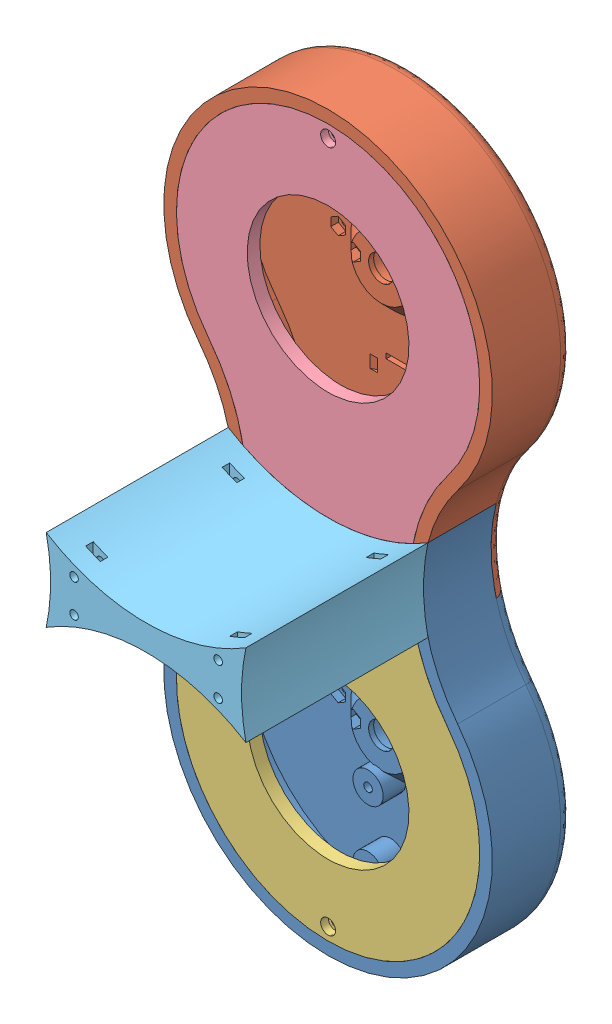
SolidWorks assembly ART2_2, configuration Predeterminado. Lengths in mm.
Overall size (130 290 113.1).
9 component instances, 7 part files, 64 mates.
Components (placement in the parent):
- Art2BodyB_Splitted_A-1: Art2BodyB_Splitted_A [Predeterminado] at (7.2829 72.9902 127.3956) x (1 0 0) z (0 -1 0) size (130 32.44 161.27)
- Art2BodyB_Splitted_B-1: Art2BodyB_Splitted_B [Predeterminado] at (7.2829 72.9902 127.3956) x (1 0 0) z (0 -1 0) size (130 32.44 161.71)
- Art2BodyBCover_Splitted_A-1: Art2BodyBCover_Splitted_A [Predeterminado] at (7.2829 72.9902 159.3956) x (-1 0 0) z (0 -1 0) size (120 7 152.99)
- Art2BodyBCover_Splitted_B-1: Art2BodyBCover_Splitted_B [Predeterminado] at (7.2829 72.9902 159.3956) x (-1 0 0) z (0 -1 0) size (120 8 152.99)
- Art2BodyUnion-1: Art2BodyUnion [Predeterminado] at (7.2829 152.9902 195.3956) x (-1 0 0) z (0 1 0) size (79 72 32.49)
- AMT-B0-W-1: AMT-B0-W [Default] at (7.2829 232.9902 123.6256) x (-0.999995 0.003209 0) z (0 0 -1) size (52.34 43.39 9.15)
- AMT-B0-W-2: AMT-B0-W [Default] at (7.2829 72.9902 123.6256) x (0.999999 -0.001499 0) z (0 0 -1) size (52.34 43.39 9.15)
- AMT-1: AMT [Default] at (7.2829 232.9902 123.6256) x (-0.999995 0.003209 0) z (0 0 -1) size (28.93 43.4 9.14)
- AMT-2: AMT [Default] at (7.2829 72.9902 123.6256) x (0.999999 -0.001499 0) z (0 0 -1) size (28.93 43.4 9.14)
Mates (geometry in assembly coordinates):
- Concéntrica1: concentric aligned: cylinder of Art2BodyB_Splitted_A-1 through (-21.2171 159.4902 109.3956) axis (0 0 1) radius 1.7; cylinder of Art2BodyB_Splitted_B-1 through (-21.2171 159.4902 109.3956) axis (0 0 1) radius 1.7
- Concéntrica2: concentric aligned: cylinder of Art2BodyB_Splitted_A-1 through (35.7829 146.4902 109.3956) axis (0 0 1) radius 1.7; cylinder of Art2BodyB_Splitted_B-1 through (35.7829 146.4902 109.3956) axis (0 0 1) radius 1.7
- Coincidente1: coincident anti-aligned: plane of Art2BodyB_Splitted_A-1 through (7.2829 72.9902 132.3956) normal (0 0 -1); plane of Art2BodyB_Splitted_B-1 through (-43.9519 192.9902 132.3956) normal (0 0 1)
- Concéntrica3: concentric anti-aligned: cylinder of Art2BodyB_Splitted_B-1 through (-3.7171 232.9902 147.3956) axis (0 0 -1) radius 1.7; cylinder of hexagon nut_3_jis-1 through (-3.7171 232.9902 134.3956) axis (0 0 1) radius 1.25
- Coincidente7: coincident anti-aligned: plane of Art2BodyB_Splitted_B-1 through (7.2829 232.9902 134.3956) normal (0 0 1); plane of hexagon nut_3_jis-1 through (-9.2171 232.9902 134.3956) normal (0 0 -1)
- Concéntrica16: concentric anti-aligned: cylinder of Art2BodyB_Splitted_A-1 through (7.2829 72.9902 136.3956) axis (0 0 -1) radius 8.2; cylinder of radial ball bearing_68_skf-1 through (7.2829 72.9902 113.2581) axis (0 0 1) radius 2.5
- Coincidente19: coincident anti-aligned: plane of Art2BodyB_Splitted_A-1 through (7.2829 72.9902 136.3956) normal (0 0 -1); plane of radial ball bearing_68_skf-1 through (7.2829 75.7902 136.3956) normal (0 0 1)
- Concéntrica17: concentric aligned: cylinder of Art2BodyB_Splitted_B-1 through (18.2829 232.9902 147.3956) axis (0 0 -1) radius 1.7; cylinder of CommonBearingFixThrough-1 through (18.2829 232.9902 130.3956) axis (0 0 -1) radius 2.95
- Concéntrica18: concentric aligned: cylinder of Art2BodyB_Splitted_B-1 through (-3.7171 232.9902 147.3956) axis (0 0 -1) radius 1.7; cylinder of CommonBearingFixThrough-1 through (-3.7171 232.9902 130.3956) axis (0 0 -1) radius 2.95
- Coincidente21: coincident aligned: plane of Art2BodyB_Splitted_B-1 through (7.2829 232.9902 131.3956) normal (0 0 -1); circle of CommonBearingFixThrough-1
- Concéntrica19: concentric aligned: cylinder of Art2BodyB_Splitted_A-1 through (18.2829 72.9902 147.3956) axis (0 0 -1) radius 1.7; cylinder of CommonBearingFixThrough-2 through (18.2829 72.9902 130.3956) axis (0 0 -1) radius 2.95
- Concéntrica20: concentric aligned: cylinder of Art2BodyB_Splitted_A-1 through (-3.7171 72.9902 147.3956) axis (0 0 -1) radius 1.7; cylinder of CommonBearingFixThrough-2 through (-3.7171 72.9902 130.3956) axis (0 0 -1) radius 2.95
- Coincidente22: coincident aligned: plane of Art2BodyB_Splitted_A-1 through (7.2829 72.9902 131.3956) normal (0 0 -1); circle of CommonBearingFixThrough-2
- Coincidente29: coincident aligned: plane of socket head cap screw_am-7 through (4.0295 58.1304 143.0356) normal (0 0 -1); plane of socket head cap screw_am-8 through (4.0295 30.1304 143.0356) normal (0 0 -1)
- Coincidente32: coincident aligned: plane of socket head cap screw_am-5 through (8.4295 252.9304 143.0356) normal (0 0 -1); plane of socket head cap screw_am-6 through (9.4829 281.1402 143.0356) normal (0 0 -1)
- Concéntrica32: concentric aligned: cylinder of Art2BodyBCover_Splitted_A-1 through (-21.2171 146.4902 154.3956) axis (0 0 1) radius 1.7; cylinder of Art2BodyBCover_Splitted_B-1 through (-21.2171 146.4902 151.3956) axis (0 0 1) radius 1.7
- Concéntrica33: concentric aligned: cylinder of Art2BodyBCover_Splitted_A-1 through (35.7829 159.4902 154.3956) axis (0 0 1) radius 1.7; cylinder of Art2BodyBCover_Splitted_B-1 through (35.7829 159.4902 151.3956) axis (0 0 1) radius 1.7
- Coincidente34: coincident anti-aligned: plane of Art2BodyBCover_Splitted_A-1 through (-43.9519 112.9902 154.3956) normal (0 0 -1); plane of Art2BodyBCover_Splitted_B-1 through (58.5177 112.9902 154.3956) normal (0 0 1)
- Concéntrica34: concentric aligned: circle of Art2BodyB_Splitted_A-1; cylinder of Art2BodyBCover_Splitted_A-1 through (7.2829 17.9902 156.3956) axis (0 0 1) radius 2.95
- Concéntrica35: concentric aligned: cylinder of Art2BodyB_Splitted_B-1 through (7.2829 287.9902 136.3956) axis (0 0 1) radius 1.7; cylinder of Art2BodyBCover_Splitted_B-1 through (7.2829 287.9902 156.3956) axis (0 0 1) radius 2.95
- Coincidente35: coincident anti-aligned: plane of Art2BodyB_Splitted_B-1 through (7.2829 232.9902 152.3956) normal (0 0 1); plane of Art2BodyBCover_Splitted_B-1 through (7.2829 232.9902 152.3956) normal (0 0 -1)
- Concéntrica36: concentric anti-aligned: cylinder of Art2BodyBCover_Splitted_B-1 through (7.2829 287.9902 171.3956) axis (0 0 -1) radius 1.7; cylinder of socket head cap screw_am-9 through (7.2829 287.9902 191.1456) axis (0 0 1) radius 1.5
- Coincidente36: coincident anti-aligned: plane of Art2BodyBCover_Splitted_B-1 through (7.2829 287.9902 156.3956) normal (0 0 1); plane of socket head cap screw_am-9 through (7.2829 290.7402 156.3956) normal (0 0 -1)
- Concéntrica37: concentric aligned: cylinder of Art2BodyBCover_Splitted_A-1 through (7.2829 17.9902 156.3956) axis (0 0 1) radius 2.95; cylinder of socket head cap screw_am-10 through (7.2829 17.9902 191.1456) axis (0 0 1) radius 1.5
- Coincidente37: coincident anti-aligned: plane of Art2BodyBCover_Splitted_A-1 through (7.2829 17.9902 156.3956) normal (0 0 1); plane of socket head cap screw_am-10 through (6.2295 20.5304 156.3956) normal (0 0 -1)
- Concéntrica38: concentric anti-aligned: cylinder of Art2BodyUnion-1 through (-21.2171 159.4902 189.3956) axis (0 0 -1) radius 1.7; cylinder of hexagon nut_3_jis-11 through (-21.2171 159.4902 166.8956) axis (0 0 1) radius 1.25
- Concéntrica39: concentric anti-aligned: cylinder of Art2BodyUnion-1 through (-21.2171 146.4902 189.3956) axis (0 0 -1) radius 1.7; cylinder of hexagon nut_3_jis-12 through (-21.2171 146.4902 166.8956) axis (0 0 1) radius 1.25
- Concéntrica40: concentric anti-aligned: cylinder of Art2BodyUnion-1 through (35.7829 146.4902 189.3956) axis (0 0 -1) radius 1.7; cylinder of hexagon nut_3_jis-13 through (35.7829 146.4902 166.8956) axis (0 0 1) radius 1.25
- Concéntrica41: concentric anti-aligned: cylinder of Art2BodyUnion-1 through (35.7829 159.4902 189.3956) axis (0 0 -1) radius 1.7; cylinder of hexagon nut_3_jis-18 through (35.7829 159.4902 166.8956) axis (0 0 1) radius 1.25
- Concéntrica42: concentric aligned: cylinder of Art2BodyUnion-1 through (-21.2171 159.4902 201.3956) axis (0 0 1) radius 1.7; cylinder of hexagon nut_3_jis-14 through (-21.2171 159.4902 222.0956) axis (0 0 1) radius 1.25
- Concéntrica43: concentric aligned: cylinder of Art2BodyUnion-1 through (-21.2171 146.4902 201.3956) axis (0 0 1) radius 1.7; cylinder of hexagon nut_3_jis-15 through (-21.2171 146.4902 222.0956) axis (0 0 1) radius 1.25
- Concéntrica44: concentric aligned: cylinder of Art2BodyUnion-1 through (35.7829 146.4902 201.3956) axis (0 0 1) radius 1.7; cylinder of hexagon nut_3_jis-16 through (35.7829 146.4902 222.0956) axis (0 0 1) radius 1.25
- Concéntrica45: concentric aligned: cylinder of Art2BodyUnion-1 through (35.7829 159.4902 201.3956) axis (0 0 1) radius 1.7; cylinder of hexagon nut_3_jis-17 through (35.7829 159.4902 222.0956) axis (0 0 1) radius 1.25
- Coincidente38: coincident aligned: plane of hexagon nut_3_jis-13 through (30.2829 146.4902 166.8956) normal (0 0 -1); plane of hexagon nut_3_jis-18 through (30.2829 159.4902 166.8956) normal (0 0 -1)
- Coincidente39: coincident aligned: plane of hexagon nut_3_jis-12 through (-26.7171 146.4902 166.8956) normal (0 0 -1); plane of hexagon nut_3_jis-13 through (30.2829 146.4902 166.8956) normal (0 0 -1)
- Coincidente40: coincident anti-aligned: circle of hexagon nut_3_jis-11; plane of hexagon nut_3_jis-18 through (30.2829 159.4902 166.8956) normal (0 0 -1)
- Coincidente41: coincident anti-aligned: plane of Art2BodyUnion-1 through (7.2829 152.9902 166.8956) normal (0 0 1); plane of hexagon nut_3_jis-11 through (-26.7171 159.4902 166.8956) normal (0 0 -1)
- Coincidente42: coincident aligned: plane of hexagon nut_3_jis-14 through (-26.7171 159.4902 223.8956) normal (0 0 1); circle of hexagon nut_3_jis-15
- Coincidente43: coincident aligned: plane of hexagon nut_3_jis-14 through (-26.7171 159.4902 223.8956) normal (0 0 1); plane of hexagon nut_3_jis-17 through (30.2829 159.4902 223.8956) normal (0 0 1)
- Coincidente44: coincident aligned: plane of hexagon nut_3_jis-16 through (30.2829 146.4902 223.8956) normal (0 0 1); plane of hexagon nut_3_jis-17 through (30.2829 159.4902 223.8956) normal (0 0 1)
- Coincidente45: coincident anti-aligned: plane of Art2BodyUnion-1 through (7.2829 152.9902 223.8956) normal (0 0 -1); plane of hexagon nut_3_jis-16 through (30.2829 146.4902 223.8956) normal (0 0 1)
- Concéntrica46: concentric anti-aligned: cylinder of Art2BodyBCover_Splitted_A-1 through (-21.2171 159.4902 154.3956) axis (0 0 1) radius 1.7; cylinder of Art2BodyUnion-1 through (-21.2171 159.4902 189.3956) axis (0 0 -1) radius 1.7
- Concéntrica47: concentric anti-aligned: cylinder of Art2BodyBCover_Splitted_A-1 through (35.7829 146.4902 154.3956) axis (0 0 1) radius 1.7; cylinder of Art2BodyUnion-1 through (35.7829 146.4902 189.3956) axis (0 0 -1) radius 1.7
- Coincidente46: coincident anti-aligned: plane of Art2BodyBCover_Splitted_A-1 through (-43.9519 112.9902 159.3956) normal (0 0 1); plane of Art2BodyUnion-1 through (64.7829 192.9902 159.3956) normal (0 0 -1)
- Concéntrica48: concentric anti-aligned: cylinder of Art2BodyB_Splitted_B-1 through (-21.2171 159.4902 109.3956) axis (0 0 1) radius 1.7; cylinder of socket head cap screw_am-13 through (-21.2171 159.4902 95.5456) axis (0 0 -1) radius 1.5
- Concéntrica49: concentric anti-aligned: cylinder of Art2BodyB_Splitted_B-1 through (35.7829 159.4902 109.3956) axis (0 0 1) radius 1.7; cylinder of socket head cap screw_am-11 through (35.7829 159.4902 95.5456) axis (0 0 -1) radius 1.5
- Concéntrica50: concentric anti-aligned: cylinder of Art2BodyB_Splitted_B-1 through (-21.2171 146.4902 109.3956) axis (0 0 1) radius 1.7; cylinder of socket head cap screw_am-14 through (-21.2171 146.4902 95.5456) axis (0 0 -1) radius 1.5
- Concéntrica51: concentric anti-aligned: cylinder of Art2BodyB_Splitted_B-1 through (35.7829 146.4902 109.3956) axis (0 0 1) radius 1.7; cylinder of socket head cap screw_am-12 through (35.7829 146.4902 95.5456) axis (0 0 -1) radius 1.5
- Coincidente47: coincident aligned: circle of socket head cap screw_am-11; plane of socket head cap screw_am-13 through (-21.2171 159.4902 127.2956) normal (0 0 -1)
- Coincidente48: coincident aligned: plane of socket head cap screw_am-13 through (-21.2171 159.4902 127.2956) normal (0 0 -1); plane of socket head cap screw_am-14 through (-21.2171 146.4902 127.2956) normal (0 0 -1)
- Coincidente49: coincident: point of socket head cap screw_am-12; plane of socket head cap screw_am-14 through (-21.2171 146.4902 127.2956) normal (0 0 -1)
- Coincidente50: coincident anti-aligned: plane of Art2BodyB_Splitted_B-1 through (35.7829 159.4902 130.2956) normal (0 0 -1); plane of socket head cap screw_am-11 through (38.0657 157.9567 130.2956) normal (0 0 1)
- Concéntrica52: concentric anti-aligned: circle of CommonBearingFixThrough-2; circle of AMT-B0-W-2
- Coincidente51: coincident anti-aligned: plane of Art2BodyB_Splitted_A-1 through (58.5177 112.9902 127.3956) normal (0 0 -1); plane of AMT-B0-W-2 through (7.2985 83.4102 127.3956) normal (0 0 1)
- Concéntrica53: concentric aligned: cylinder of CommonBearingFixThrough-1 through (7.2829 232.9902 127.3956) axis (0 0 1) radius 5; cylinder of AMT-B0-W-1 through (7.2829 232.9902 127.3957) axis (0 0 1) radius 6.3
- Coincidente52: coincident anti-aligned: plane of Art2BodyB_Splitted_B-1 through (58.5177 112.9902 127.3956) normal (0 0 -1); plane of AMT-B0-W-1 through (7.2495 222.5702 127.3956) normal (0 0 1)
- Concéntrica59: concentric aligned: cylinder of Art2BodyB_Splitted_B-1 through (-15.7296 232.9902 137.3956) axis (0 0 -1) radius 1.7; cylinder of socket button head cap screw_am-1 through (-15.7296 232.9902 123.2456) axis (0 0 -1) radius 1.5
- Coincidente58: coincident anti-aligned: plane of AMT-B0-W-1 through (-15.6475 233.2775 124.8956) normal (0 0 -1); plane of socket button head cap screw_am-1 through (-16.7839 234.0572 124.8956) normal (0 0 1)
- Concéntrica62: concentric aligned: cylinder of AMT-B0-W-2 through (7.2829 72.9902 127.3957) axis (0 0 1) radius 6.3; cylinder of AMT-2 through (7.2829 72.9902 118.404) axis (0 0 1) radius 6.3
- Concéntrica63: concentric aligned: cylinder of AMT-B0-W-2 through (-3.171 88.7539 123.6256) axis (0 0 -1) radius 1.4351; cylinder of AMT-2 through (-3.171 88.7539 123.6256) axis (0 0 -1) radius 1.4351
- Coincidente62: coincident anti-aligned: plane of AMT-B0-W-2 through (7.6047 87.5497 125.6956) normal (0 0 -1); plane of AMT-2 through (7.6047 87.5497 125.6956) normal (0 0 1)
- Concéntrica64: concentric aligned: cylinder of AMT-B0-W-1 through (7.2829 232.9902 127.3957) axis (0 0 1) radius 6.3; cylinder of AMT-1 through (7.2829 232.9902 118.404) axis (0 0 1) radius 6.3
- Concéntrica65: concentric aligned: cylinder of AMT-B0-W-1 through (17.7098 217.2086 123.6256) axis (0 0 -1) radius 1.4351; cylinder of AMT-1 through (17.7098 217.2086 123.6256) axis (0 0 -1) radius 1.4351
- Coincidente63: coincident anti-aligned: plane of AMT-B0-W-1 through (6.9362 218.4312 125.6956) normal (0 0 -1); plane of AMT-1 through (6.9362 218.4312 125.6956) normal (0 0 1)
